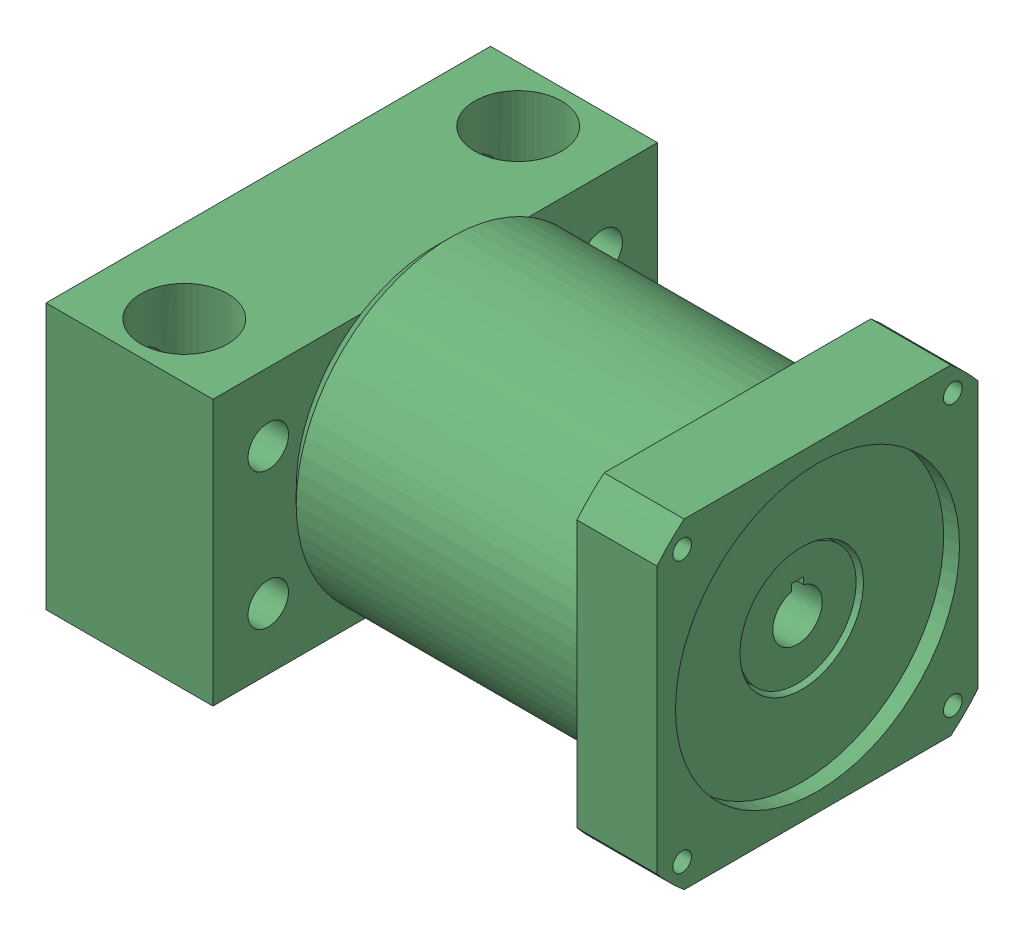
SolidWorks assembly EndCode1_17-U3, configuration Valor predeterminado. Lengths in mm.
Overall size (141.48 82.55 114.3).
5 component instances, 5 part files, 0 mates.
Components (placement in the parent):
- Place Holder-1: Place Holder [Valor predeterminado] at origin size (0.38 0.51 0.51)
- EndMachining_17-3K-1: EndMachining_17-3K [Valor predeterminado] x (0 0 1) z (-1 0 0) size (17.01 17.01 92.71)
- EZM_EZM-3017-34-1: EZM_EZM-3017-34 [Valor predeterminado] at (43.18 -38.1 57.15) x (0 0 -1) z (1 0 0) size (114.3 82.55 141.22)
- LockNut(1)_N-03-1: LockNut(1)_N-03 [Valor predeterminado] at (48.514 0 0) x (1 0 0) z (0 0.998865 0.047634) size (8.64 28.41 28.51)
- Spacer-1: Spacer [Valor predeterminado] at origin size (48.51 22.35 22.35)
